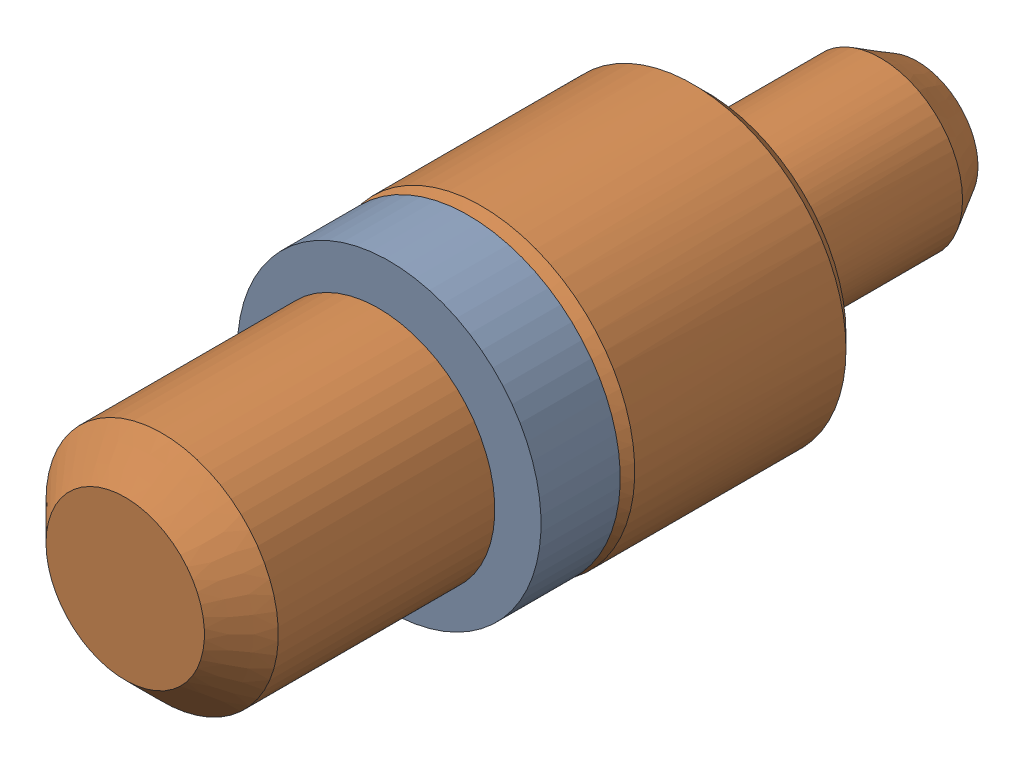
SolidWorks assembly Pogo Pin Asmbly_2, configuration Default. Lengths in mm.
Overall size (2.95 2.95 7.62).
2 component instances, 2 part files, 0 mates.
Components (placement in the parent):
- Pogo O-Ring-1: Pogo O-Ring [Default] at (73.025 70.993 -6.223) size (2.92 2.92 0.76)
- Pogo Contact Pin-1: Pogo Contact Pin [Default] at (73.025 70.993 -6.223) size (2.95 2.95 7.62)
